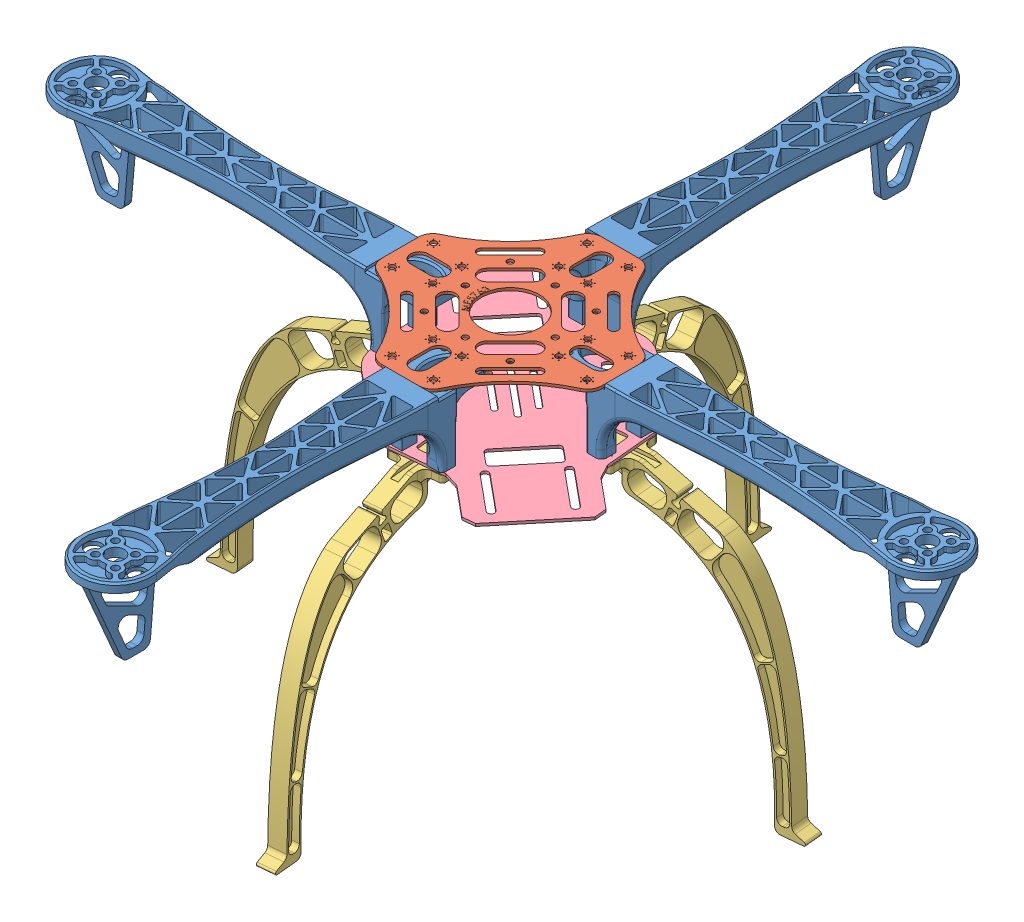
SolidWorks assembly Assem1, configuration Default. Lengths in mm.
Overall size (501 190.84 501).
10 component instances, 4 part files, 25 mates.
Components (placement in the parent):
- arm-1: arm [Default] at (-208.6988 139.1397 276.6634) size (220 54.84 46.12)
- base_top-1: base_top [Default] at (21.5512 139.1397 272.3254) x (-0.707107 0 -0.707107) z (-0.707107 0 0.707107) size (108.1 1.5 108.1)
- leg-1: leg [Default] at (-39.891 95.1397 277.1775) x (0.995595 0 -0.093761) z (0.093761 0 0.995595) size (116.19 150 30)
- arm-2: arm [Default] at (251.8012 139.1397 266.0215) x (-1 0 0) z (0 0 -1) size (220 54.84 46.12)
- arm-3: arm [Default] at (27.952 139.1397 502.5754) x (0 0 -1) z (1 0 0) size (220 54.84 46.12)
- arm-4: arm [Default] at (17.3101 139.1397 42.0754) x (0 0 1) z (-1 0 0) size (220 54.84 46.12)
- base_bottom-2: base_bottom [Default] at (22.5826 99.1397 271.294) x (0.770291 0 0.637693) z (-0.637693 0 0.770291) size (182 1.5 119)
- leg-2: leg [Default] at (28.4661 95.1397 333.7676) x (-0.093761 0 -0.995595) z (0.995595 0 -0.093761) size (116.19 150 30)
- leg-3: leg [Default] at (16.6991 95.1397 208.8205) x (0.093761 0 0.995595) z (-0.995595 0 0.093761) size (116.19 150 30)
- leg-4: leg [Default] at (85.0561 95.1397 265.4105) x (-0.995595 0 0.093761) z (-0.093761 0 -0.995595) size (116.19 150 30)
Mates (geometry in assembly coordinates):
- Coincident1: coincident anti-aligned: plane of arm-1 through (-40.9488 137.6397 256.4134) normal (0 1 0); plane of base_top-1 through (113.4751 137.6397 180.4015) normal (0 -1 0)
- Coincident2: coincident anti-aligned: plane of arm-1 through (-40.9488 139.1397 256.4134) normal (1 0 0); plane of base_top-1 through (-40.9488 137.6397 288.2461) normal (-1 0 0)
- Coincident3: coincident anti-aligned: plane of base_top-1 through (113.4751 137.6397 180.4015) normal (0 -1 0); plane of arm-2 through (84.0512 137.6397 286.2715) normal (0 1 0)
- Coincident4: coincident anti-aligned: plane of base_top-1 through (84.0512 137.6397 256.4047) normal (1 0 0); plane of arm-2 through (84.0512 139.1397 286.2715) normal (-1 0 0)
- Coincident5: coincident anti-aligned: plane of base_top-1 through (113.4751 137.6397 180.4015) normal (0 -1 0); plane of arm-3 through (7.702 137.6397 334.8254) normal (0 1 0)
- Coincident6: coincident anti-aligned: plane of base_top-1 through (5.6305 137.6397 334.8254) normal (0 0 1); plane of arm-3 through (7.702 139.1397 334.8254) normal (0 0 -1)
- Coincident7: coincident anti-aligned: plane of base_top-1 through (113.4751 137.6397 180.4015) normal (0 -1 0); plane of arm-4 through (37.5601 137.6397 209.8254) normal (0 1 0)
- Coincident8: coincident anti-aligned: plane of base_top-1 through (37.4719 137.6397 209.8254) normal (0 0 -1); plane of arm-4 through (37.5601 139.1397 209.8254) normal (0 0 1)
- Coincident11: coincident anti-aligned: plane of leg-1 through (-39.891 99.1397 277.1775) normal (0 1 0); plane of base_bottom-2 through (22.5826 99.1397 271.294) normal (0 -1 0)
- Concentric1: concentric anti-aligned: cylinder of leg-1 through (-32.886 99.1397 287.5665) axis (0 -1 0) radius 1.75; cylinder of base_bottom-2 through (-32.886 99.1397 287.5665) axis (0 1 0) radius 1.75
- Concentric2: concentric anti-aligned: cylinder of leg-1 through (-34.9488 99.1397 265.6634) axis (0 -1 0) radius 1.75; cylinder of base_bottom-2 through (-34.9488 99.1397 265.6634) axis (0 1 0) radius 1.75
- Coincident13: coincident anti-aligned: plane of base_bottom-2 through (22.5826 99.1397 271.294) normal (0 -1 0); plane of leg-2 through (28.4661 99.1397 333.7676) normal (0 1 0)
- Concentric3: concentric anti-aligned: cylinder of base_bottom-2 through (16.952 99.1397 328.8254) axis (0 1 0) radius 1.75; cylinder of leg-2 through (16.952 99.1397 328.8254) axis (0 -1 0) radius 1.75
- Concentric4: concentric anti-aligned: cylinder of base_bottom-2 through (38.8551 99.1397 326.7627) axis (0 1 0) radius 1.75; cylinder of leg-2 through (38.8551 99.1397 326.7627) axis (0 -1 0) radius 1.75
- Coincident14: coincident anti-aligned: plane of base_bottom-2 through (22.5826 99.1397 271.294) normal (0 -1 0); plane of leg-3 through (16.6991 99.1397 208.8205) normal (0 1 0)
- Concentric5: concentric anti-aligned: cylinder of base_bottom-2 through (28.2132 99.1397 213.7627) axis (0 1 0) radius 1.75; cylinder of leg-3 through (28.2132 99.1397 213.7627) axis (0 -1 0) radius 1.75
- Concentric6: concentric anti-aligned: cylinder of base_bottom-2 through (6.3101 99.1397 215.8254) axis (0 1 0) radius 1.75; cylinder of leg-3 through (6.3101 99.1397 215.8254) axis (0 -1 0) radius 1.75
- Coincident15: coincident anti-aligned: plane of base_bottom-2 through (22.5826 99.1397 271.294) normal (0 -1 0); plane of leg-4 through (85.0561 99.1397 265.4105) normal (0 1 0)
- Concentric7: concentric anti-aligned: cylinder of base_bottom-2 through (80.114 99.1397 276.9246) axis (0 1 0) radius 1.75; cylinder of leg-4 through (80.114 99.1397 276.9246) axis (0 -1 0) radius 1.75
- Concentric8: concentric anti-aligned: cylinder of base_bottom-2 through (78.0512 99.1397 255.0215) axis (0 1 0) radius 1.75; cylinder of leg-4 through (78.0512 99.1397 255.0215) axis (0 -1 0) radius 1.75
- Coincident16: coincident anti-aligned: plane of arm-1 through (-106.05 100.6397 288.5264) normal (0 -1 0); plane of base_bottom-2 through (22.5826 100.6397 271.294) normal (0 1 0)
- Concentric9: concentric anti-aligned: cylinder of arm-1 through (-34.9488 106.6397 265.6634) axis (0 -1 0) radius 1.5; cylinder of base_bottom-2 through (-34.9488 99.1397 265.6634) axis (0 1 0) radius 1.75
- Concentric10: concentric anti-aligned: cylinder of arm-2 through (78.0512 106.6397 255.0215) axis (0 -1 0) radius 1.5; cylinder of base_bottom-2 through (78.0512 99.1397 255.0215) axis (0 1 0) radius 1.75
- Concentric11: concentric anti-aligned: cylinder of arm-3 through (16.952 106.6397 328.8254) axis (0 -1 0) radius 1.5; cylinder of base_bottom-2 through (16.952 99.1397 328.8254) axis (0 1 0) radius 1.75
- Concentric12: concentric aligned: cylinder of arm-4 through (6.3101 106.6397 215.8254) axis (0 -1 0) radius 1.5; cylinder of leg-3 through (6.3101 99.1397 215.8254) axis (0 -1 0) radius 1.75
